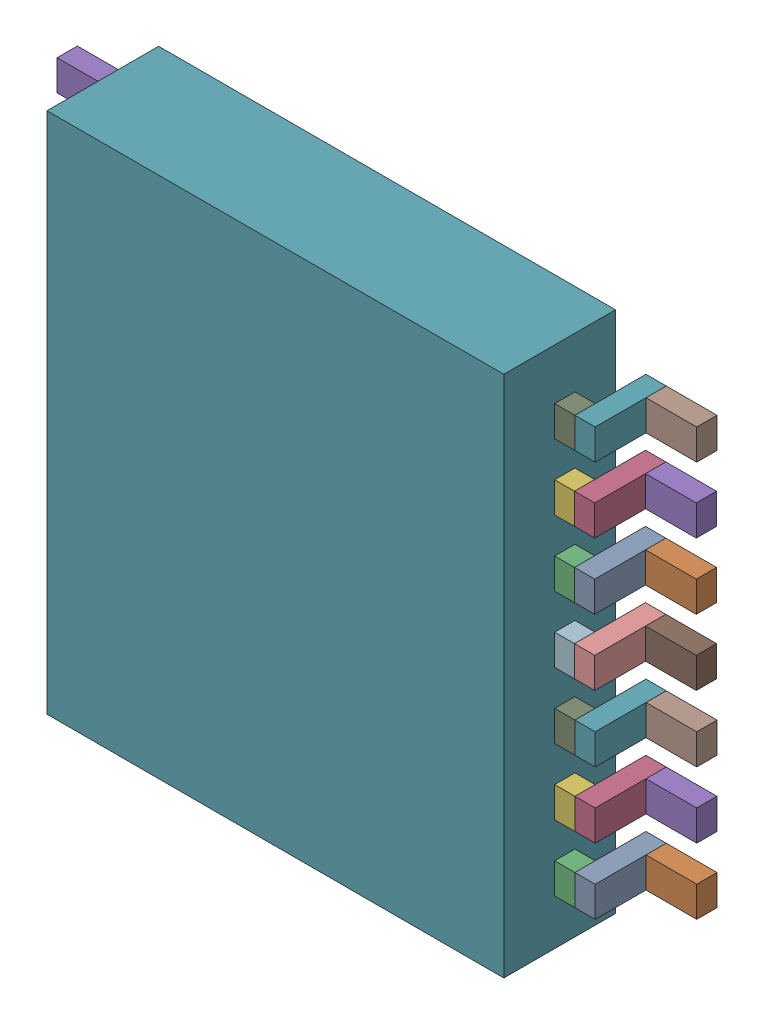
SolidWorks assembly U13, configuration Default. Lengths in mm.
Overall size (6.3 5.15 1.2).
86 component instances, 4 part files, 0 mates.
Components (placement in the parent):
- 836750064-1: 836750064 [Default] at (113.1 46.05 0) size (0.2 0.3 0.7)
  - Extruded_24-1: Extruded_24 [Default] at origin size (0.2 0.3 0.7)
- 836751344-1: 836751344 [Default] at (113.45 46.05 0) size (0.5 0.3 0.2)
  - Extruded_25-1: Extruded_25 [Default] at origin size (0.5 0.3 0.2)
- 836749808-1: 836749808 [Default] at (112.9 46.05 0.5) size (0.2 0.3 0.2)
  - Extruded_26-1: Extruded_26 [Default] at origin size (0.2 0.3 0.2)
- 836750064-2: 836750064 [Default] at (113.1 46.7 0) size (0.2 0.3 0.7)
  - Extruded_24-1: Extruded_24 [Default] at origin size (0.2 0.3 0.7)
- 836751344-2: 836751344 [Default] at (113.45 46.7 0) size (0.5 0.3 0.2)
  - Extruded_25-1: Extruded_25 [Default] at origin size (0.5 0.3 0.2)
- 836749808-2: 836749808 [Default] at (112.9 46.7 0.5) size (0.2 0.3 0.2)
  - Extruded_26-1: Extruded_26 [Default] at origin size (0.2 0.3 0.2)
- 836750064-3: 836750064 [Default] at (113.1 47.35 0) size (0.2 0.3 0.7)
  - Extruded_24-1: Extruded_24 [Default] at origin size (0.2 0.3 0.7)
- 836751344-3: 836751344 [Default] at (113.45 47.35 0) size (0.5 0.3 0.2)
  - Extruded_25-1: Extruded_25 [Default] at origin size (0.5 0.3 0.2)
- 836749808-3: 836749808 [Default] at (112.9 47.35 0.5) size (0.2 0.3 0.2)
  - Extruded_26-1: Extruded_26 [Default] at origin size (0.2 0.3 0.2)
- 836750064-4: 836750064 [Default] at (113.0954 48 0) size (0.2 0.3 0.7)
  - Extruded_24-1: Extruded_24 [Default] at origin size (0.2 0.3 0.7)
- 836751344-4: 836751344 [Default] at (113.4454 48 0) size (0.5 0.3 0.2)
  - Extruded_25-1: Extruded_25 [Default] at origin size (0.5 0.3 0.2)
- 836749808-4: 836749808 [Default] at (112.8954 48 0.5) size (0.2 0.3 0.2)
  - Extruded_26-1: Extruded_26 [Default] at origin size (0.2 0.3 0.2)
- 836750064-5: 836750064 [Default] at (113.0954 48.65 0) size (0.2 0.3 0.7)
  - Extruded_24-1: Extruded_24 [Default] at origin size (0.2 0.3 0.7)
- 836751344-5: 836751344 [Default] at (113.4454 48.65 0) size (0.5 0.3 0.2)
  - Extruded_25-1: Extruded_25 [Default] at origin size (0.5 0.3 0.2)
- 836749808-5: 836749808 [Default] at (112.8954 48.65 0.5) size (0.2 0.3 0.2)
  - Extruded_26-1: Extruded_26 [Default] at origin size (0.2 0.3 0.2)
- 836750064-6: 836750064 [Default] at (113.0954 49.3 0) size (0.2 0.3 0.7)
  - Extruded_24-1: Extruded_24 [Default] at origin size (0.2 0.3 0.7)
- 836751344-6: 836751344 [Default] at (113.4454 49.3 0) size (0.5 0.3 0.2)
  - Extruded_25-1: Extruded_25 [Default] at origin size (0.5 0.3 0.2)
- 836749808-6: 836749808 [Default] at (112.8954 49.3 0.5) size (0.2 0.3 0.2)
  - Extruded_26-1: Extruded_26 [Default] at origin size (0.2 0.3 0.2)
- 836750064-7: 836750064 [Default] at (113.1 49.95 0) size (0.2 0.3 0.7)
  - Extruded_24-1: Extruded_24 [Default] at origin size (0.2 0.3 0.7)
- 836751344-7: 836751344 [Default] at (113.45 49.95 0) size (0.5 0.3 0.2)
  - Extruded_25-1: Extruded_25 [Default] at origin size (0.5 0.3 0.2)
- 836749808-7: 836749808 [Default] at (112.9 49.95 0.5) size (0.2 0.3 0.2)
  - Extruded_26-1: Extruded_26 [Default] at origin size (0.2 0.3 0.2)
- 836750064-8: 836750064 [Default] at (108 46.05 0) size (0.2 0.3 0.7)
  - Extruded_24-1: Extruded_24 [Default] at origin size (0.2 0.3 0.7)
- 836751344-8: 836751344 [Default] at (107.65 46.05 0) size (0.5 0.3 0.2)
  - Extruded_25-1: Extruded_25 [Default] at origin size (0.5 0.3 0.2)
- 836749808-8: 836749808 [Default] at (108.2 46.05 0.5) size (0.2 0.3 0.2)
  - Extruded_26-1: Extruded_26 [Default] at origin size (0.2 0.3 0.2)
- 836750064-9: 836750064 [Default] at (108 46.7 0) size (0.2 0.3 0.7)
  - Extruded_24-1: Extruded_24 [Default] at origin size (0.2 0.3 0.7)
- 836751344-9: 836751344 [Default] at (107.65 46.7 0) size (0.5 0.3 0.2)
  - Extruded_25-1: Extruded_25 [Default] at origin size (0.5 0.3 0.2)
- 836749808-9: 836749808 [Default] at (108.2 46.7 0.5) size (0.2 0.3 0.2)
  - Extruded_26-1: Extruded_26 [Default] at origin size (0.2 0.3 0.2)
- 836750064-10: 836750064 [Default] at (108 47.35 0) size (0.2 0.3 0.7)
  - Extruded_24-1: Extruded_24 [Default] at origin size (0.2 0.3 0.7)
- 836751344-10: 836751344 [Default] at (107.65 47.35 0) size (0.5 0.3 0.2)
  - Extruded_25-1: Extruded_25 [Default] at origin size (0.5 0.3 0.2)
- 836749808-10: 836749808 [Default] at (108.2 47.35 0.5) size (0.2 0.3 0.2)
  - Extruded_26-1: Extruded_26 [Default] at origin size (0.2 0.3 0.2)
- 836750064-11: 836750064 [Default] at (108 48 0) size (0.2 0.3 0.7)
  - Extruded_24-1: Extruded_24 [Default] at origin size (0.2 0.3 0.7)
- 836751344-11: 836751344 [Default] at (107.65 48 0) size (0.5 0.3 0.2)
  - Extruded_25-1: Extruded_25 [Default] at origin size (0.5 0.3 0.2)
- 836749808-11: 836749808 [Default] at (108.2 48 0.5) size (0.2 0.3 0.2)
  - Extruded_26-1: Extruded_26 [Default] at origin size (0.2 0.3 0.2)
- 836750064-12: 836750064 [Default] at (108 48.65 0) size (0.2 0.3 0.7)
  - Extruded_24-1: Extruded_24 [Default] at origin size (0.2 0.3 0.7)
- 836751344-12: 836751344 [Default] at (107.65 48.65 0) size (0.5 0.3 0.2)
  - Extruded_25-1: Extruded_25 [Default] at origin size (0.5 0.3 0.2)
- 836749808-12: 836749808 [Default] at (108.2 48.65 0.5) size (0.2 0.3 0.2)
  - Extruded_26-1: Extruded_26 [Default] at origin size (0.2 0.3 0.2)
- 836750064-13: 836750064 [Default] at (108 49.3 0) size (0.2 0.3 0.7)
  - Extruded_24-1: Extruded_24 [Default] at origin size (0.2 0.3 0.7)
- 836751344-13: 836751344 [Default] at (107.65 49.3 0) size (0.5 0.3 0.2)
  - Extruded_25-1: Extruded_25 [Default] at origin size (0.5 0.3 0.2)
- 836749808-13: 836749808 [Default] at (108.2 49.3 0.5) size (0.2 0.3 0.2)
  - Extruded_26-1: Extruded_26 [Default] at origin size (0.2 0.3 0.2)
- 836749808-14: 836749808 [Default] at (108.2 49.95 0.5) size (0.2 0.3 0.2)
  - Extruded_26-1: Extruded_26 [Default] at origin size (0.2 0.3 0.2)
- 836751344-14: 836751344 [Default] at (107.65 49.95 0) size (0.5 0.3 0.2)
  - Extruded_25-1: Extruded_25 [Default] at origin size (0.5 0.3 0.2)
- 836750064-14: 836750064 [Default] at (108 49.95 0) size (0.2 0.3 0.7)
  - Extruded_24-1: Extruded_24 [Default] at origin size (0.2 0.3 0.7)
- 859196720-1: 859196720 [Default] at (110.55 48.025 0.1) size (4.5 5.15 1.1)
  - Extruded_27-1: Extruded_27 [Default] at origin size (4.5 5.15 1.1)
